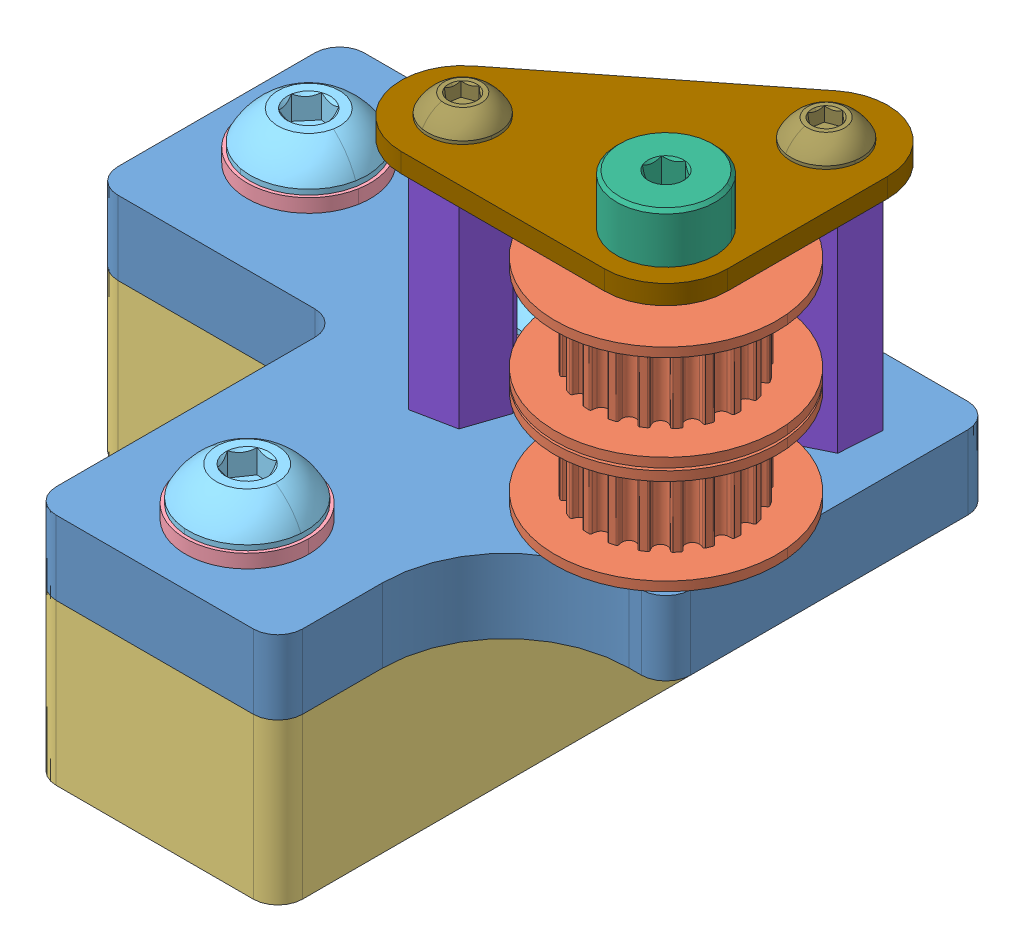
SolidWorks assembly right_double_pulley_corner_bracket_assembly.STEP, configuration Default. Lengths in mm.
Overall size (56.38 47.91 45).
23 component instances, 12 part files, 0 mates.
Components (placement in the parent):
- alum_double_pulley_corner_bracketr_Right Double Pulley Corner Bracket.STEP-1: alum_double_pulley_corner_bracketr_Right Double Pulley Corner Bracket.STEP [Default] at (-62.2708 23.0327 20.6343) size (53 6 45)
- 20t_idler_5mm_bore.STEP-1: 20t_idler_5mm_bore.STEP [Default] at (37.2292 29.7559 40.6343) x (-0.103173 0 -0.994663) z (0.994663 0 -0.103173) size (18 8.5 18)
- double_pulley_corner_bracket_Right Machined Bracket Spacer.STEP-1: double_pulley_corner_bracket_Right Machined Bracket Spacer.STEP [Default] at (-49.2708 10.0327 65.6343) size (40 13 45)
- m5_stainless_steel_washer_90965A160_90965A160.STEP-1: m5_stainless_steel_washer_90965A160_90965A160.STEP [Default] at (20.7292 29.0327 30.6343) x (0.699222 0 0.714904) z (0 1 0) size (10 10 1.1)
- m5_stainless_steel_washer_90965A160_90965A160.STEP-2: m5_stainless_steel_washer_90965A160_90965A160.STEP [Default] at (-1.7708 29.0327 30.6343) x (-0.983728 0 -0.179665) z (0 1 0) size (10 10 1.1)
- m5_stainless_steel_washer_90965A160_90965A160.STEP-3: m5_stainless_steel_washer_90965A160_90965A160.STEP [Default] at (20.7292 29.0327 58.1343) x (1 0 0) z (0 1 0) size (10 10 1.1)
- m5_25mm_buttonhead_screw_92095A216_92095A216.STEP-1: m5_25mm_buttonhead_screw_92095A216_92095A216.STEP [Default] at (-1.7708 32.8827 30.6343) x (-0.180007 0 0.983665) z (0 1 0) size (9.5 9.5 27.76)
- m5_25mm_buttonhead_screw_92095A216_92095A216.STEP-2: m5_25mm_buttonhead_screw_92095A216_92095A216.STEP [Default] at (20.7292 32.8827 30.6343) x (0.658392 0 -0.752675) z (0 1 0) size (9.5 9.5 27.76)
- m5_25mm_buttonhead_screw_92095A216_92095A216.STEP-3: m5_25mm_buttonhead_screw_92095A216_92095A216.STEP [Default] at (20.7292 32.8827 58.1343) x (-0.076489 0 0.99707) z (0 1 0) size (9.5 9.5 27.76)
- m4_shoulder_screw_5mm_d_20mm_l_90278A374_90278A374.STEP-1: m4_shoulder_screw_5mm_d_20mm_l_90278A374_90278A374.STEP [Default] at (37.2292 53.0327 40.6343) x (0.419286 0 0.907854) z (0 1 0) size (8 8 29.01)
- m5_shim_0.2mm_thick_98089A246_98089A246.STEP-1: m5_shim_0.2mm_thick_98089A246_98089A246.STEP [Default] at (37.2292 29.5559 40.6343) x (-0.103173 0 -0.994663) z (0.994663 0 -0.103173) size (10 0.2 10)
- m5_shim_0.2mm_thick_98089A246_98089A246.STEP-2: m5_shim_0.2mm_thick_98089A246_98089A246.STEP [Default] at (37.2292 38.2559 40.6343) x (-0.103173 0 -0.994663) z (0.994663 0 -0.103173) size (10 0.2 10)
- 20t_idler_5mm_bore.STEP-2: 20t_idler_5mm_bore.STEP [Default] at (37.2292 38.4559 40.6343) x (-0.103173 0 -0.994663) z (0.994663 0 -0.103173) size (18 8.5 18)
- m3_18mm_hex_standoff_6mm_wide_95947A525_95947A525.STEP-1: m3_18mm_hex_standoff_6mm_wide_95947A525_95947A525.STEP [Default] at (20.7292 38.0327 40.6343) x (-0.947495 0 -0.319772) z (0 -1 0) size (6 6.93 18)
- m3_18mm_hex_standoff_6mm_wide_95947A525_95947A525.STEP-2: m3_18mm_hex_standoff_6mm_wide_95947A525_95947A525.STEP [Default] at (37.2292 38.0327 27.6343) x (-0.558669 0 0.82939) z (0 -1 0) size (6 6.93 18)
- back_pulley_reinforcement_plate.STEP-1: back_pulley_reinforcement_plate.STEP [Default] at (37.2292 48.6027 40.6343) x (-1 0 0) z (0 0 1) size (26.5 1.57 23)
- m5_locking_t_nut_20x20_generic.STEP-1: m5_locking_t_nut_20x20_generic.STEP [Default] at (17.7292 5.1327 58.1343) x (0 0 -1) z (1 0 0) size (10 4.5 6)
- m5_locking_t_nut_20x20_generic.STEP-2: m5_locking_t_nut_20x20_generic.STEP [Default] at (17.7292 5.1327 30.6343) x (0 0 -1) z (1 0 0) size (10 4.5 6)
- m5_locking_t_nut_20x20_generic.STEP-3: m5_locking_t_nut_20x20_generic.STEP [Default] at (-1.7708 5.1327 27.6343) size (10 4.5 6)
- m3_10mm_buttonhead_screw_92095A182_92095A182.STEP-1: m3_10mm_buttonhead_screw_92095A182_92095A182.STEP [Default] at (37.2292 21.3827 27.6343) x (-0.480761 0 0.876852) z (0 -1 0) size (5.7 5.7 11.66)
- m3_10mm_buttonhead_screw_92095A182_92095A182.STEP-2: m3_10mm_buttonhead_screw_92095A182_92095A182.STEP [Default] at (20.7292 21.3827 40.6343) x (-0.480761 0 0.876852) z (0 -1 0) size (5.7 5.7 11.66)
- m3_6mm_buttonhead_screw_92095A179_92095A179.STEP-1: m3_6mm_buttonhead_screw_92095A179_92095A179.STEP [Default] at (37.2292 50.2527 27.6343) x (-0.985858 0 -0.167581) z (0 1 0) size (5.7 5.7 7.66)
- m3_6mm_buttonhead_screw_92095A179_92095A179.STEP-2: m3_6mm_buttonhead_screw_92095A179_92095A179.STEP [Default] at (20.7292 50.2527 40.6343) x (-0.985858 0 -0.167581) z (0 1 0) size (5.7 5.7 7.66)
